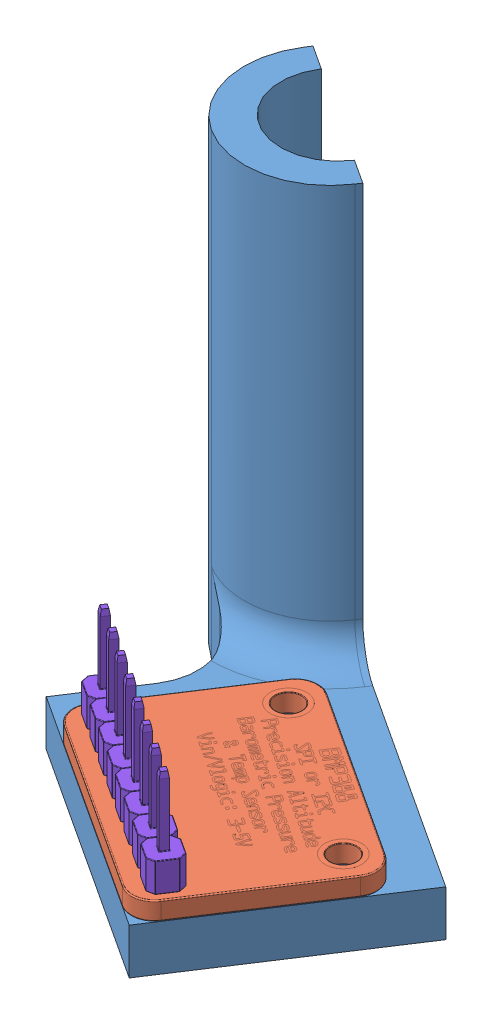
SolidWorks assembly BMP_with_holder, configuration Default. Lengths in mm.
Overall size (44.43 40 38.62).
21 component instances, 8 part files, 3 mates.
Components (placement in the parent):
- pressure_sensor_holder-1: pressure_sensor_holder [Default] at (-65.9526 8.5608 43.0261) x (0.837169 0 0.546944) z (-0.546944 0 0.837169) size (40 40 20)
- BMP388_breakout.STEP-1: BMP388_breakout.STEP [Default] at (-44.8327 23.185 49.8545) x (-0.837169 0 -0.546944) z (-0.546944 0 0.837169) size (21.6 11.54 16.6)
  - BMP388_carcassa.STEP-1: BMP388_carcassa.STEP [Default] at (-3.5843 9.0242 9.2349) size (21.6 1.61 16.6)
  - BMP280___ _________.STEP-1: BMP280___ _________.STEP [Default] at (7.7816 10.6443 16.6543) x (-1 0 0) z (0 -1 0) size (2.5 2 0.97)
  - Res0603.STEP-1: Res0603.STEP [Default] at (10.1227 10.8493 14.9076) x (1 0 0) z (0 0 -1) size (1.6 0.45 0.8)
  - Res0603.STEP-2: Res0603.STEP [Default] at (3.5723 10.8492 19.717) x (0 0 -1) z (-1 0 0) size (1.6 0.45 0.8)
  - LDO SOT23.STEP-1: LDO SOT23.STEP [Default] at (-1.2671 11.1742 16.8912) size (3 1.1 2.5)
  - cap0603.STEP-1: cap0603.STEP [Default] at (2.0876 11.0242 16.9925) x (0 0 1) z (-1 0 0) size (1.6 0.8 0.9)
  - cap0603.STEP-2: cap0603.STEP [Default] at (-1.3533 11.0242 19.3508) size (1.6 0.8 0.9)
  - cap0603.STEP-3: cap0603.STEP [Default] at (3.4154 11.0242 16.997) x (0 0 1) z (-1 0 0) size (1.6 0.8 0.9)
  - Res0603.STEP-3: Res0603.STEP [Default] at (13.1908 10.8493 14.9262) x (1 0 0) z (0 0 -1) size (1.6 0.45 0.8)
  - User Library-SW3dPS-SOT363_D_faut.STEP-1: User Library-SW3dPS-SOT363_D_faut.STEP [Default] at (15.4727 11.4142 17.4519) size (2.1 0.99 2)
  - User Library-SW3dPS-SOT363_D_faut.STEP-2: User Library-SW3dPS-SOT363_D_faut.STEP [Default] at (11.2741 11.4143 19.0108) size (2.1 0.99 2)
  - MalePinHeader.STEP-1: MalePinHeader.STEP [Default] at (14.8329 6.4841 22.0117) size (2.54 11.54 2.54)
  - MalePinHeader.STEP-2: MalePinHeader.STEP [Default] at (9.7562 6.4841 22.0162) size (2.54 11.54 2.54)
  - MalePinHeader.STEP-3: MalePinHeader.STEP [Default] at (7.2156 6.4841 21.9989) size (2.54 11.54 2.54)
  - MalePinHeader.STEP-4: MalePinHeader.STEP [Default] at (-0.4008 6.4841 21.997) size (2.54 11.54 2.54)
  - MalePinHeader.STEP-5: MalePinHeader.STEP [Default] at (-2.9499 6.4841 22.0117) size (2.54 11.54 2.54)
  - MalePinHeader.STEP-6: MalePinHeader.STEP [Default] at (12.3028 6.4841 22.0061) size (2.54 11.54 2.54)
  - MalePinHeader.STEP-7: MalePinHeader.STEP [Default] at (2.1379 6.4841 22.0105) size (2.54 11.54 2.54)
  - MalePinHeader.STEP-8: MalePinHeader.STEP [Default] at (4.6865 6.4841 22.0155) size (2.54 11.54 2.54)
Mates (geometry in assembly coordinates):
- Coincident1: coincident anti-aligned: plane of pressure_sensor_holder-1 through (-65.9526 12.5608 43.0261) normal (0 1 0); plane of BMP388_breakout.STEP-1/BMP388_carcassa.STEP-1 through (-46.883 12.5608 59.5461) normal (0 -1 0)
- Coincident2: coincident aligned: plane of BMP388_breakout.STEP-1/BMP388_carcassa.STEP-1 through (-55.9623 12.5608 73.4431) normal (-0.546944 0 0.837169); plane of pressure_sensor_holder-1 through (-76.8915 12.5608 59.7695) normal (-0.546944 0 0.837169)
- Coincident3: coincident aligned: plane of BMP388_breakout.STEP-1/BMP388_carcassa.STEP-1 through (-46.883 12.5608 59.5461) normal (0.837169 0 0.546944); plane of pressure_sensor_holder-1 through (-45.0234 12.5608 56.6997) normal (0.837169 0 0.546944)
